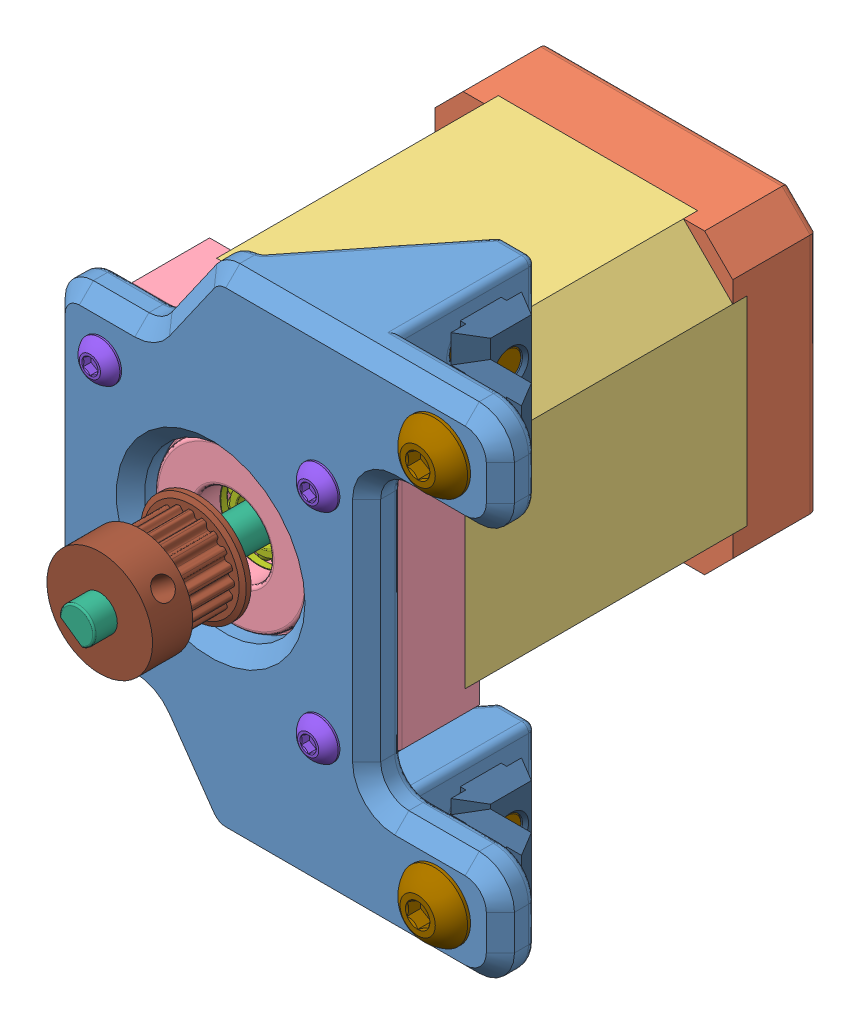
SolidWorks assembly Motor_Mount_With_Nema17_60mm, configuration ReversedPulley. Lengths in mm.
Overall size (63.8 70.3 84.16).
25 component instances, 11 part files, 41 mates.
Components (placement in the parent):
- External_Motor-1: External_Motor [Default] at origin size (63.8 70.3 24)
- NEMA_17_60mm_1.5A-1: NEMA_17_60mm_1.5A [Default] at (10.3955 -4.6172 -60) size (42.3 42.3 84.16)
  - Base-1: Base [Default] at (-10.3955 4.6172 0) size (42.3 42.3 12)
  - Body_60mm-1: Body_60mm [Default] at (-10.3955 4.6172 10) size (42.3 42.3 40)
  - FaceCap-1: FaceCap [Default] at (-10.3955 4.6172 60) x (-1 0 0) z (0 0 -1) size (42.3 42.3 14)
  - 3mmX50mm_Sockethead(McMaster_91290A137)-1: 3mmX50mm_Sockethead(McMaster_91290A137) [91290A137] at (-25.8955 -10.8828 53) x (-0.535522 -0.844521 0) z (0 0 1) size (5.5 5.5 53.26)
  - 3mmX50mm_Sockethead(McMaster_91290A137)-2: 3mmX50mm_Sockethead(McMaster_91290A137) [91290A137] at (5.1045 20.1172 53) x (-0.078076 -0.996947 0) z (0 0 1) size (5.5 5.5 53.26)
  - 3mmX50mm_Sockethead(McMaster_91290A137)-3: 3mmX50mm_Sockethead(McMaster_91290A137) [91290A137] at (-25.8955 20.1172 53) x (0.373638 -0.927575 0) z (0 0 1) size (5.5 5.5 53.26)
  - 3mmX50mm_Sockethead(McMaster_91290A137)-4: 3mmX50mm_Sockethead(McMaster_91290A137) [91290A137] at (5.1045 -10.8828 53) x (-0.438078 -0.898937 0) z (0 0 1) size (5.5 5.5 53.26)
  - Shaft_60mm-1: Shaft_60mm [Default] at (-10.3955 4.6172 0) x (0.574856 0.818255 0) z (0 0 1) size (5 5 84.02)
  - instrument ball bearing_68_am(PreviewCfg)-1: instrument ball bearing_68_am(PreviewCfg) [Default] at (-10.3955 4.6172 56.5875) x (0 0 -1) z (0.994238 0.107199 0) size (3.17 12.7 12.7)
  - instrument ball bearing_68_am(PreviewCfg)-2: instrument ball bearing_68_am(PreviewCfg) [Default] at (-10.3955 4.6172 3.4125) x (0 0 1) z (-0.739703 -0.672934 0) size (3.17 12.7 12.7)
- 3mmX10mm_Buttonhead(McMaster_94500A223)-3: 3mmX10mm_Buttonhead(McMaster_94500A223) [94500A223] at (-15.5 -15.5 6.65) x (-1 0 0) z (0 0 1) size (5.7 5.7 11.96)
- 3mmX10mm_Buttonhead(McMaster_94500A223)-4: 3mmX10mm_Buttonhead(McMaster_94500A223) [94500A223] at (15.5 15.5 6.65) x (-1 0 0) z (0 0 1) size (5.7 5.7 11.96)
- 3mmX10mm_Buttonhead(McMaster_94500A223)-5: 3mmX10mm_Buttonhead(McMaster_94500A223) [94500A223] at (-15.5 15.5 6.65) x (-0.5 -0.866025 0) z (0 0 1) size (5.7 5.7 11.96)
- 3mmX10mm_Buttonhead(McMaster_94500A223)-6: 3mmX10mm_Buttonhead(McMaster_94500A223) [94500A223] at (15.5 -15.5 6.65) x (-0.5 0.866025 0) z (0 0 1) size (5.7 5.7 11.96)
- 5mmX10mm_Buttonhead(McMaster_91239A224)-1: 5mmX10mm_Buttonhead(McMaster_91239A224) [91239A224] at (32.15 -27.65 7.75) size (9.5 9.5 13.21)
- 5mmX10mm_Buttonhead(McMaster_91239A224)-2: 5mmX10mm_Buttonhead(McMaster_91239A224) [91239A224] at (32.15 27.65 7.75) size (9.5 9.5 13.21)
- 5mmX10mm_Buttonhead(McMaster_91239A224)-3: 5mmX10mm_Buttonhead(McMaster_91239A224) [91239A224] at (14.4 -28.65 -10) x (0 0 1) z (-1 0 0) size (9.5 9.5 13.21)
- 5mmX10mm_Buttonhead(McMaster_91239A224)-4: 5mmX10mm_Buttonhead(McMaster_91239A224) [91239A224] at (14.4 28.65 -10) x (0 0 1) z (-1 0 0) size (9.5 9.5 13.21)
- HNTTSN5-5-1: HNTTSN5-5 [Default] at (23.35 -28.65 -10) x (-1 0 0) z (0 -1 0) size (4.3 10 10)
- HNTTSN5-5-2: HNTTSN5-5 [Default] at (32.15 -27.65 -1.2) x (0 0 1) z (0 -1 0) size (4.3 10 10)
- HNTTSN5-5-3: HNTTSN5-5 [Default] at (23.35 28.65 -10) x (-1 0 0) z (0 -1 0) size (4.3 10 10)
- HNTTSN5-5-4: HNTTSN5-5 [Default] at (32.15 27.65 -1.2) x (0 0 1) z (0 -1 0) size (4.3 10 10)
- GT2_Aluminum_Timing_Pulley_20_Tooth-1: GT2_Aluminum_Timing_Pulley_20_Tooth [Default] at (0 0 20.754) x (0.802532 0.59661 0) z (-0.59661 0.802532 0) size (15 14 15)
Mates (geometry in assembly coordinates):
- Coincident1: coincident anti-aligned: plane of External_Motor-1 through (36.15 30.15 0) normal (0 0 -1); plane of NEMA_17_60mm_1.5A-1/FaceCap-1 through (0 0 0) normal (0 0 1)
- Concentric1: concentric anti-aligned: circle of External_Motor-1; circle of NEMA_17_60mm_1.5A-1/FaceCap-1
- Parallel1: parallel aligned: plane of External_Motor-1 through (22.15 -16.15 5) normal (1 0 0); plane of NEMA_17_60mm_1.5A-1/FaceCap-1 through (21.15 17.15 -12) normal (1 0 0)
- Coincident10: coincident anti-aligned: plane of External_Motor-1 through (36.15 30.15 5) normal (0 0 1); plane of 5mmX10mm_Buttonhead(McMaster_91239A224)-1 through (32.15 -32.4 5) normal (0 0 -1)
- Coincident11: coincident anti-aligned: plane of External_Motor-1 through (36.15 30.15 5) normal (0 0 1); plane of 5mmX10mm_Buttonhead(McMaster_91239A224)-2 through (32.15 22.9 5) normal (0 0 -1)
- Coincident12: coincident anti-aligned: plane of External_Motor-1 through (17.15 -28.65 -10) normal (-1 0 0); plane of 5mmX10mm_Buttonhead(McMaster_91239A224)-3 through (17.15 -33.4 -10) normal (1 0 0)
- Coincident13: coincident anti-aligned: plane of External_Motor-1 through (17.15 28.65 -10) normal (-1 0 0); plane of 5mmX10mm_Buttonhead(McMaster_91239A224)-4 through (17.15 23.9 -10) normal (1 0 0)
- Concentric6: concentric anti-aligned: cylinder of External_Motor-1 through (17.15 28.65 -10) axis (1 0 0) radius 2.65; circle of 5mmX10mm_Buttonhead(McMaster_91239A224)-4
- Concentric7: concentric anti-aligned: cylinder of External_Motor-1 through (17.15 -28.65 -10) axis (1 0 0) radius 2.65; circle of 5mmX10mm_Buttonhead(McMaster_91239A224)-3
- Concentric8: concentric anti-aligned: cylinder of External_Motor-1 through (32.15 -27.65 5) axis (0 0 -1) radius 2.65; circle of 5mmX10mm_Buttonhead(McMaster_91239A224)-1
- Concentric9: concentric anti-aligned: cylinder of External_Motor-1 through (32.15 27.65 5) axis (0 0 -1) radius 2.65; circle of 5mmX10mm_Buttonhead(McMaster_91239A224)-2
- Concentric10: concentric aligned: cylinder of External_Motor-1 through (17.15 -28.65 -10) axis (1 0 0) radius 2.65; cylinder of HNTTSN5-5-1 through (23.35 -28.65 -10) axis (1 0 0) radius 2.067
- Concentric11: concentric aligned: cylinder of External_Motor-1 through (17.15 28.65 -10) axis (1 0 0) radius 2.65; cylinder of HNTTSN5-5-3 through (23.35 28.65 -10) axis (1 0 0) radius 2.067
- Concentric12: concentric aligned: cylinder of External_Motor-1 through (32.15 27.65 5) axis (0 0 -1) radius 2.65; cylinder of HNTTSN5-5-4 through (32.15 27.65 -1.2) axis (0 0 -1) radius 2.067
- Concentric13: concentric aligned: cylinder of External_Motor-1 through (32.15 -27.65 5) axis (0 0 -1) radius 2.65; cylinder of HNTTSN5-5-2 through (32.15 -27.65 -1.2) axis (0 0 -1) radius 2.067
- Parallel6: parallel aligned: plane of External_Motor-1 through (2.15 -35.15 5) normal (0 -1 0); plane of HNTTSN5-5-1 through (23.35 -33.65 -10) normal (0 -1 0)
- Parallel7: parallel aligned: plane of External_Motor-1 through (2.15 -35.15 5) normal (0 -1 0); plane of HNTTSN5-5-2 through (32.15 -32.65 -1.2) normal (0 -1 0)
- Parallel8: parallel aligned: plane of External_Motor-1 through (2.15 -35.15 5) normal (0 -1 0); plane of HNTTSN5-5-4 through (32.15 22.65 -1.2) normal (0 -1 0)
- Parallel9: parallel aligned: plane of External_Motor-1 through (2.15 -35.15 5) normal (0 -1 0); plane of HNTTSN5-5-3 through (23.35 23.65 -10) normal (0 -1 0)
- Distance1: distance = 2 mm anti-aligned: plane of External_Motor-1 through (22.15 -22.15 0) normal (1 0 0); plane of HNTTSN5-5-1 through (24.15 -33.65 -12.9) normal (-1 0 0)
- Distance2: distance = 2 mm anti-aligned: plane of External_Motor-1 through (22.15 -22.15 0) normal (1 0 0); plane of HNTTSN5-5-3 through (24.15 23.65 -12.9) normal (-1 0 0)
- Distance3: distance = 2 mm anti-aligned: plane of External_Motor-1 through (36.15 30.15 0) normal (0 0 -1); plane of HNTTSN5-5-2 through (37.15 -32.65 -2) normal (0 0 1)
- Distance4: distance = 2 mm anti-aligned: plane of External_Motor-1 through (36.15 30.15 0) normal (0 0 -1); plane of HNTTSN5-5-4 through (37.15 22.65 -2) normal (0 0 1)
- Concentric14: concentric aligned: cylinder of GT2_Aluminum_Timing_Pulley_20_Tooth-1 through (0 0 22) axis (0 0 -1) radius 2.5; cylinder of NEMA_17_60mm_1.5A-1/Shaft_60mm-1 through (0 0 24) axis (0 0 -1) radius 2.5
- Coincident14: coincident aligned: plane of 3mmX10mm_Buttonhead(McMaster_94500A223)-3 through (-15.5 -12.65 5) normal (0 0 -1); plane of 3mmX10mm_Buttonhead(McMaster_94500A223)-5 through (-17.9682 16.925 5) normal (0 0 -1)
- Coincident15: coincident aligned: plane of 3mmX10mm_Buttonhead(McMaster_94500A223)-3 through (-15.5 -12.65 5) normal (0 0 -1); plane of 3mmX10mm_Buttonhead(McMaster_94500A223)-6 through (17.9682 -14.075 5) normal (0 0 -1)
- Coincident16: coincident aligned: plane of 3mmX10mm_Buttonhead(McMaster_94500A223)-3 through (-15.5 -12.65 5) normal (0 0 -1); plane of 3mmX10mm_Buttonhead(McMaster_94500A223)-4 through (15.5 18.35 5) normal (0 0 -1)
- Coincident17: coincident anti-aligned: plane of External_Motor-1 through (36.15 30.15 5) normal (0 0 1); plane of 3mmX10mm_Buttonhead(McMaster_94500A223)-3 through (-15.5 -12.65 5) normal (0 0 -1)
- Concentric15: concentric anti-aligned: cylinder of External_Motor-1 through (-15.5 -15.5 5) axis (0 0 -1) radius 1.65; cylinder of 3mmX10mm_Buttonhead(McMaster_94500A223)-3 through (-15.5 -15.5 6.65) axis (0 0 1) radius 2.85
- Concentric16: concentric anti-aligned: cylinder of External_Motor-1 through (-15.5 15.5 5) axis (0 0 -1) radius 1.65; cylinder of 3mmX10mm_Buttonhead(McMaster_94500A223)-5 through (-15.5 15.5 6.65) axis (0 0 1) radius 2.85
- Concentric17: concentric anti-aligned: cylinder of External_Motor-1 through (15.5 -15.5 5) axis (0 0 -1) radius 1.65; cylinder of 3mmX10mm_Buttonhead(McMaster_94500A223)-6 through (15.5 -15.5 6.65) axis (0 0 1) radius 2.85
- Concentric18: concentric anti-aligned: cylinder of External_Motor-1 through (15.5 15.5 5) axis (0 0 -1) radius 1.65; cylinder of 3mmX10mm_Buttonhead(McMaster_94500A223)-4 through (15.5 15.5 6.65) axis (0 0 1) radius 2.85
- Parallel10: parallel aligned: plane of External_Motor-1 through (-22.65 -18.65 5) normal (-1 0 0); plane of 3mmX10mm_Buttonhead(McMaster_94500A223)-3 through (-14.5 -16.0774 5.495) normal (-1 0 0)
- Parallel11: parallel aligned: plane of External_Motor-1 through (-22.65 -18.65 5) normal (-1 0 0); plane of 3mmX10mm_Buttonhead(McMaster_94500A223)-5 through (-14.5 14.9226 5.495) normal (-1 0 0)
- Parallel12: parallel aligned: plane of External_Motor-1 through (-22.65 -18.65 5) normal (-1 0 0); plane of 3mmX10mm_Buttonhead(McMaster_94500A223)-4 through (16.5 14.9226 5.495) normal (-1 0 0)
- Parallel13: parallel aligned: plane of External_Motor-1 through (-22.65 -18.65 5) normal (-1 0 0); plane of 3mmX10mm_Buttonhead(McMaster_94500A223)-6 through (16.5 -16.0774 5.495) normal (-1 0 0)
- Parallel14: parallel aligned: plane of 5mmX10mm_Buttonhead(McMaster_91239A224)-1 through (30.65 -26.784 5.825) normal (1 0 0); plane of External_Motor-1 through (41.15 -30.15 5) normal (1 0 0)
- Parallel15: parallel aligned: plane of 5mmX10mm_Buttonhead(McMaster_91239A224)-1 through (30.65 -26.784 5.825) normal (1 0 0); plane of 5mmX10mm_Buttonhead(McMaster_91239A224)-2 through (30.65 28.516 5.825) normal (1 0 0)
- Parallel16: parallel aligned: plane of External_Motor-1 through (22.15 -22.15 -19) normal (0 0 -1); plane of 5mmX10mm_Buttonhead(McMaster_91239A224)-3 through (16.325 -29.516 -8.5) normal (0 0 -1)
- Parallel17: parallel aligned: plane of External_Motor-1 through (22.15 -22.15 -19) normal (0 0 -1); plane of 5mmX10mm_Buttonhead(McMaster_91239A224)-4 through (16.325 27.784 -8.5) normal (0 0 -1)
- Concentric19: concentric anti-aligned: cylinder of GT2_Aluminum_Timing_Pulley_20_Tooth-1 through (0 0 6.754) axis (0 0 1) radius 2.5; cylinder of NEMA_17_60mm_1.5A-1/Shaft_60mm-1 through (0 0 24) axis (0 0 -1) radius 2.5
